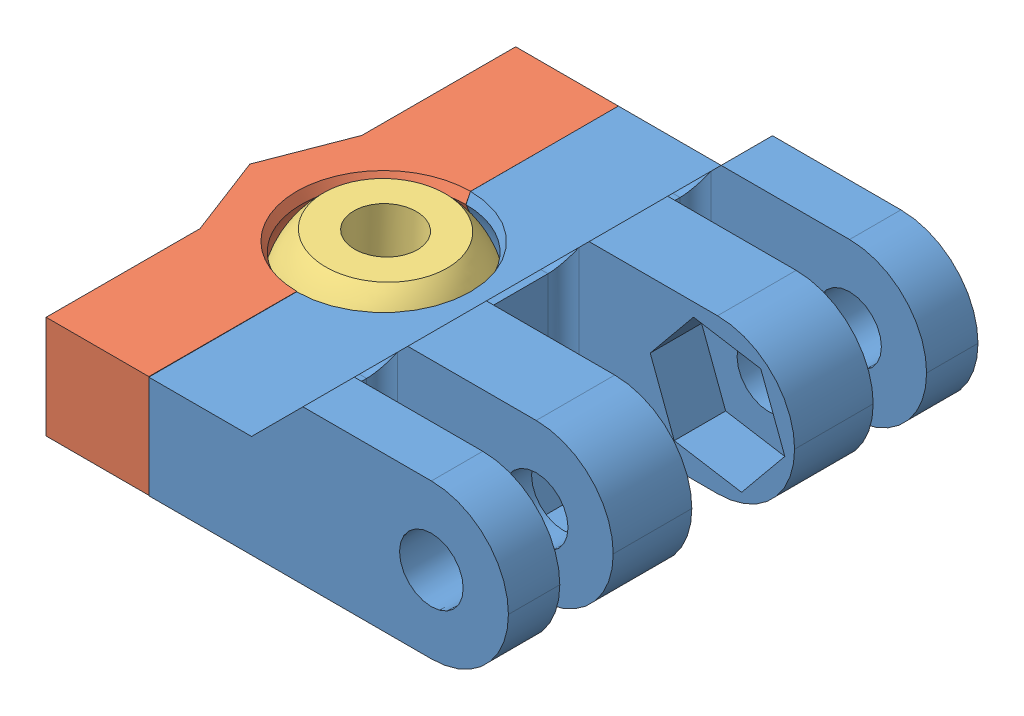
SolidWorks assembly experiment1, configuration Default. Lengths in mm.
Overall size (48.02 16.28 45.71).
3 component instances, 3 part files, 3 mates.
Components (placement in the parent):
- knuckleholder-1: knuckleholder [experiment] at (27.5866 -29.4453 32.2866) size (35 15 45.7)
- experiment thing-1: experiment thing [Default] at (-7.4134 -19.4526 -13.419) x (0 -0.001127 -0.999999) z (-1 0 0) size (45.7 10 13.02)
- experimentball-1: experimentball [Default] at (-7.4134 -24.4269 9.4366) x (0.998532 -0.03069 0.044631) z (-0.044586 0.00214 0.999003) size (17 12.04 17)
Mates (geometry in assembly coordinates):
- Concentric4: concentric anti-aligned: cylinder of knuckleholder-1 through (2.5866 -24.4453 -6.9134) axis (-1 0 0) radius 4; cylinder of experiment thing-1 through (-22.4134 -24.4453 -6.9134) axis (1 0 0) radius 3
- Concentric5: concentric: sphere of knuckleholder-1; sphere of experimentball-1
- Coincident3: coincident anti-aligned: plane of knuckleholder-1 through (-7.4134 -29.4453 32.2866) normal (-1 0 0); plane of experiment thing-1 through (-7.4134 -29.4526 -13.4078) normal (1 0 0)
